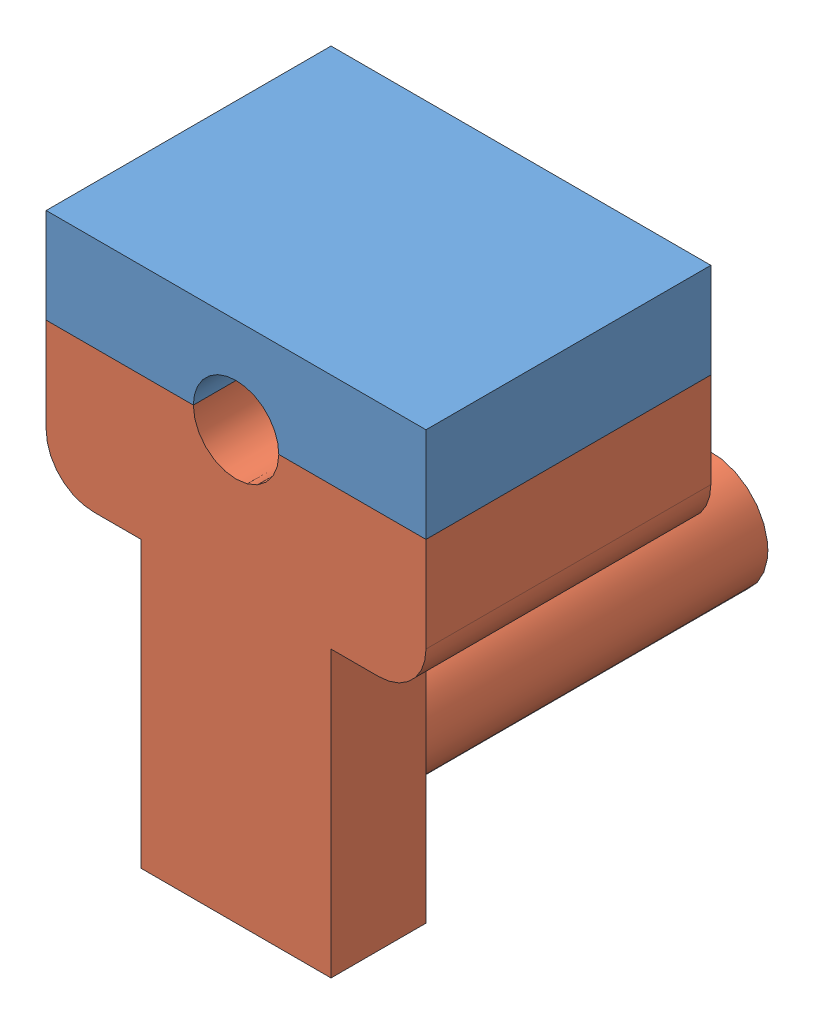
SolidWorks assembly Assemblage support fillet, configuration Défaut. Lengths in mm.
Overall size (40 55 50).
2 component instances, 2 part files, 2 mates.
Components (placement in the parent):
- support_fillet2_virsion2-1: support_fillet2_virsion2 [Défaut] at (-4.3035 15.6137 40) size (40 10 30)
- support_fillet1_virsion2-1: support_fillet1_virsion2 [Défaut] at (-4.3035 -14.3863 70) x (1 0 0) z (0 0 -1) size (40 45 50)
Mates (geometry in assembly coordinates):
- Coïncidente1: coincident anti-aligned: line of support_fillet2_virsion2-1 through (5.6965 0.6137 70) axis (-1 0 0); line of support_fillet1_virsion2-1 through (-9.8035 0.6137 70) axis (1 0 0)
- Coïncidente2: coincident anti-aligned: line of support_fillet2_virsion2-1 through (5.6965 0.6137 40) axis (0 0 1); line of support_fillet1_virsion2-1 through (5.6965 0.6137 70) axis (0 0 -1)
